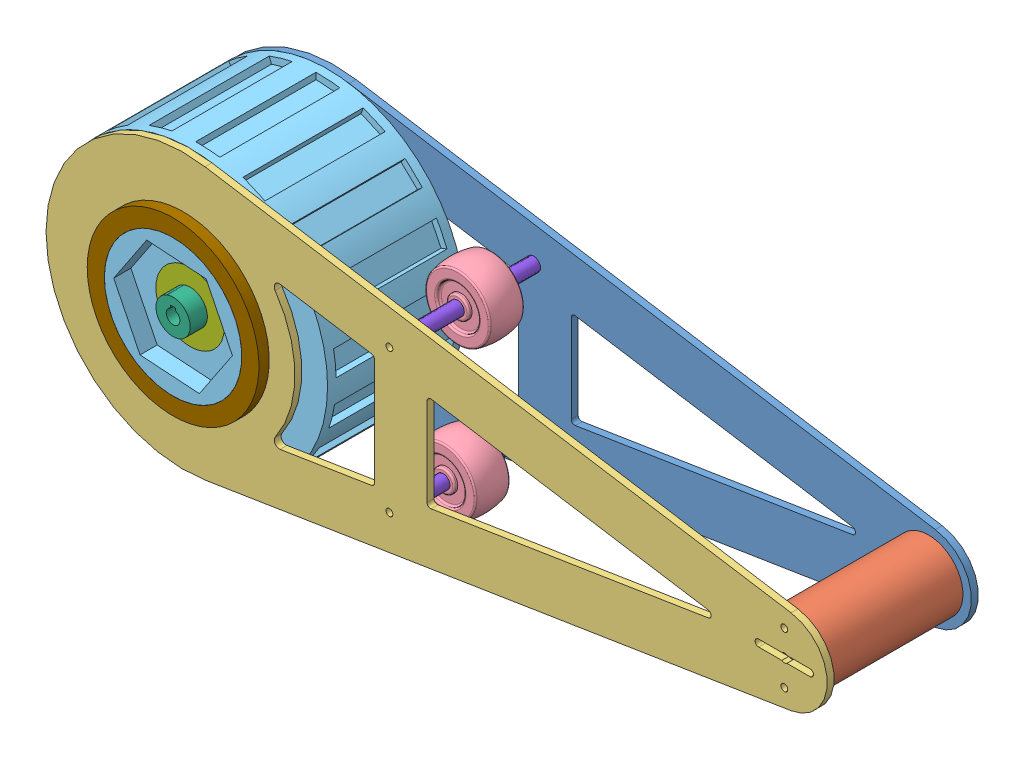
SolidWorks assembly 装配体副履带, configuration 默认. Lengths in mm.
Overall size (482.14 214.28 98).
12 component instances, 9 part files, 22 mates.
Components (placement in the parent):
- 侧履带框-1: 侧履带框 [默认] at (-119.7189 15.9797 42) size (455 160 4)
- 副履带小轮-1: 副履带小轮 [默认] at (230.2811 15.9797 42) x (0.956781 -0.290809 0) z (0 0 1) size (40 40 80)
- 侧履带内框-1: 侧履带内框 [默认] at (-119.7189 15.9797 126) size (455 160 4)
- 小轮子-2: 小轮子 [默认] at (0.2811 57.6401 76.3741) x (0.999994 0.0035 0) z (-0.0035 0.999994 0) size (40 20 40)
- 副履带大轮-1: 副履带大轮 [默认] at (-119.7189 15.9797 42) x (-0.442506 0.896766 0) z (0 0 1) size (160 160 90)
- 副履带轴-1: 副履带轴 [默认] at (-119.7189 15.9797 38) size (50 50 98)
- 轴承1-1: 轴承1 [默认] at (-119.7189 15.9797 112) size (40 40 10)
- 轴承1-2: 轴承1 [默认] at (-119.7189 15.9797 52) size (40 40 10)
- 圆柱-1: 圆柱 [默认] at (0.2811 57.6401 42) size (8 8 80)
- 圆柱-2: 圆柱 [默认] at (0.2811 -25.6808 42) x (0.987351 0.158553 0) z (0 0 1) size (8 8 80)
- 小轮子-3: 小轮子 [默认] at (0.2811 -25.6808 84.7036) x (0.98679 0.162007 0) z (-0.162007 0.98679 0) size (40 20 40)
- 10080轴承-1: 10080轴承 [默认] at (-119.7189 15.9797 122) size (100 100 10)
Mates (geometry in assembly coordinates):
- 同心1: concentric: cylinder of assembly; cylinder of assembly; cylinder of 侧履带框-1 through (230.2811 15.9797 32) axis (0 0 1) radius 2.5; cylinder of 副履带小轮-1 through (230.2811 15.9797 122) axis (0 0 -1) radius 2.5
- 重合2: coincident: plane of assembly; plane of assembly; plane of 侧履带框-1 through (-119.7189 15.9797 42) normal (0 0 1); plane of 副履带小轮-1 through (230.2811 15.9797 42) normal (0 0 -1)
- 重合3: coincident: plane of assembly; plane of assembly; plane of 副履带小轮-1 through (230.2811 15.9797 122) normal (0 0 1); plane of 侧履带内框-1 through (-119.7189 15.9797 122) normal (0 0 -1)
- 同心3: concentric: cylinder of assembly; cylinder of assembly; cylinder of 副履带小轮-1 through (230.2811 15.9797 122) axis (0 0 -1) radius 20; cylinder of 侧履带内框-1 through (230.2811 15.9797 116) axis (0 0 1) radius 2.5
- 同心4: concentric: cylinder of assembly; cylinder of assembly; cylinder of 侧履带内框-1 through (0.2811 57.6401 46) axis (0 0 1) radius 2; cylinder of 小轮子-2 through (0.2811 57.6401 66.3741) axis (0 0 -1) radius 3
- 重合4: coincident: plane of assembly; plane of assembly; plane of 侧履带框-1 through (-119.7189 15.9797 42) normal (0 0 1); plane of 副履带大轮-1 through (-119.7189 15.9797 42) normal (0 0 -1)
- 重合5: coincident: cylinder of assembly; circle of assembly; cylinder of 侧履带框-1 through (-119.7189 15.9797 38) axis (0 0 1) radius 80; circle of 侧履带内框-1
- 同心6: concentric: cylinder of assembly; cylinder of assembly; cylinder of 侧履带内框-1 through (-119.7189 15.9797 116) axis (0 0 1) radius 50; cylinder of 副履带大轮-1 through (-119.7189 15.9797 132) axis (0 0 -1) radius 40
- 同心7: concentric: cylinder of assembly; cylinder of assembly; cylinder of 副履带大轮-1 through (-119.7189 15.9797 122) axis (0 0 -1) radius 10.5; cylinder of 副履带轴-1 through (-119.7189 15.9797 132) axis (0 0 -1) radius 10
- 重合7: coincident: plane of assembly; plane of assembly; plane of 副履带大轮-1 through (-119.7189 15.9797 132) normal (0 0 1); plane of 副履带轴-1 through (-119.7189 15.9797 132) normal (0 0 1)
- 同心8: concentric: cylinder of assembly; cylinder of assembly; cylinder of 侧履带框-1 through (-119.7189 0.9797 38) axis (0 0 1) radius 1.5; cylinder of 副履带轴-1 through (-119.7189 0.9797 38) axis (0 0 -1) radius 1.5
- 重合8: coincident: plane of assembly; plane of assembly; plane of 副履带大轮-1 through (-119.7189 15.9797 112) normal (0 0 1); plane of 轴承1-1 through (-119.7189 15.9797 112) normal (0 0 -1)
- 重合10: coincident: plane of assembly; plane of assembly; plane of 副履带大轮-1 through (-119.7189 15.9797 62) normal (0 0 -1); plane of 轴承1-2 through (-119.7189 15.9797 62) normal (0 0 1)
- 同心9: concentric: cylinder of assembly; cylinder of assembly; cylinder of 副履带大轮-1 through (-119.7189 15.9797 62) axis (0 0 -1) radius 20; cylinder of 轴承1-2 through (-119.7189 15.9797 62) axis (0 0 -1) radius 20
- 同心10: concentric: cylinder of assembly; cylinder of assembly; cylinder of 副履带大轮-1 through (-119.7189 15.9797 112) axis (0 0 1) radius 20; cylinder of 轴承1-1 through (-119.7189 15.9797 122) axis (0 0 -1) radius 10
- 同心11: concentric: cylinder of assembly; cylinder of assembly; cylinder of 侧履带内框-1 through (0.2811 57.6401 46) axis (0 0 1) radius 2; cylinder of 圆柱-1 through (0.2811 57.6401 122) axis (0 0 -1) radius 4
- 重合11: coincident: plane of assembly; plane of assembly; plane of 侧履带内框-1 through (-119.7189 15.9797 122) normal (0 0 -1); plane of 圆柱-1 through (0.2811 57.6401 122) normal (0 0 1)
- 同心12: concentric: cylinder of assembly; cylinder of assembly; cylinder of 侧履带内框-1 through (0.2811 -25.6808 46) axis (0 0 1) radius 2; cylinder of 小轮子-3 through (0.2811 -25.6808 74.7036) axis (0 0 -1) radius 3
- 同心13: concentric: circle of assembly; cylinder of assembly; circle of 侧履带内框-1; cylinder of 圆柱-2 through (0.2811 -25.6808 122) axis (0 0 -1) radius 4
- 重合12: coincident: plane of assembly; plane of assembly; plane of 侧履带内框-1 through (-119.7189 15.9797 122) normal (0 0 -1); plane of 圆柱-2 through (0.2811 -25.6808 122) normal (0 0 1)
- 同心14: concentric: cylinder of assembly; cylinder of assembly; cylinder of 副履带大轮-1 through (-119.7189 15.9797 132) axis (0 0 -1) radius 40; cylinder of 10080轴承-1 through (-119.7189 15.9797 132) axis (0 0 -1) radius 40
- 重合13: coincident: plane of assembly; circle of assembly; plane of 副履带大轮-1 through (-119.7189 15.9797 122) normal (0 0 1); circle of 10080轴承-1
